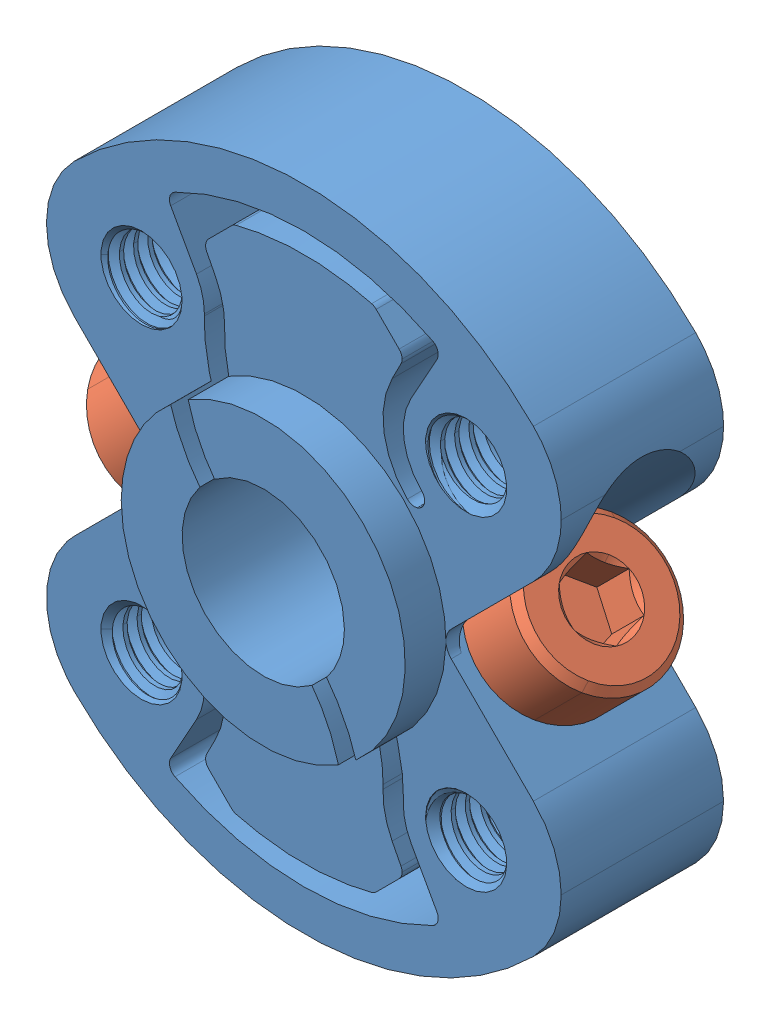
SolidWorks assembly 8mm Hub 1309-0016-0008, configuration Default. Lengths in mm.
Overall size (28.36 32 10.95).
3 component instances, 2 part files, 0 mates.
Components (placement in the parent):
- 1309-0016-0008.STEP-1: 1309-0016-0008.STEP [Default] at (-17.0099 0.5776 8.1447) size (25.38 32 10)
- 2800-0004-0014_90128A207.STEP-1: 2800-0004-0014_90128A207.STEP [Default] at (-19.0628 -10.5411 8.1447) x (0.5 -0.5 0.707107) z (-0.707107 -0.707107 0) size (7 7 18.01)
- 2800-0004-0014_90128A207.STEP-2: 2800-0004-0014_90128A207.STEP [Default] at (-14.9571 11.6963 8.1447) x (-0.5 0.5 0.707107) z (0.707107 0.707107 0) size (7 7 18.01)
